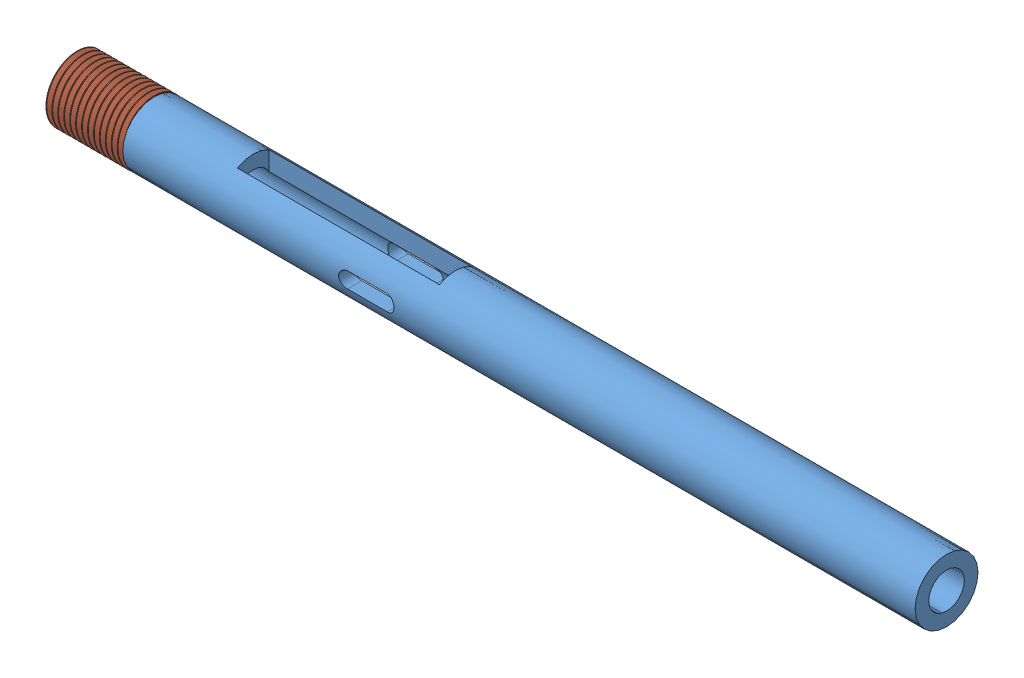
SolidWorks assembly slider assembly v-4 06-Nov-2017, configuration Default. Lengths in mm.
Overall size (110.35 13 13).
2 component instances, 2 part files, 2 mates.
Components (placement in the parent):
- wheel_handle_body_slider v-4 06-Nov-2017-1: wheel_handle_body_slider v-4 06-Nov-2017 [Default] at (-10.0168 48.9172 77.5775) size (100 7.94 7.94)
- M8X0.75-1: M8X0.75 [91290A414] at (-10.0168 48.9172 77.5775) x (0 0 -1) z (1 0 0) size (13 13 10.51)
Mates (geometry in assembly coordinates):
- Coincident1: coincident anti-aligned: plane of wheel_handle_body_slider v-4 06-Nov-2017-1 through (-10.0168 48.9172 77.5775) normal (-1 0 0); plane of M8X0.75-1 through (-10.0168 48.9172 77.5775) normal (1 0 0)
- Concentric1: concentric anti-aligned: circle of wheel_handle_body_slider v-4 06-Nov-2017-1; circle of M8X0.75-1
